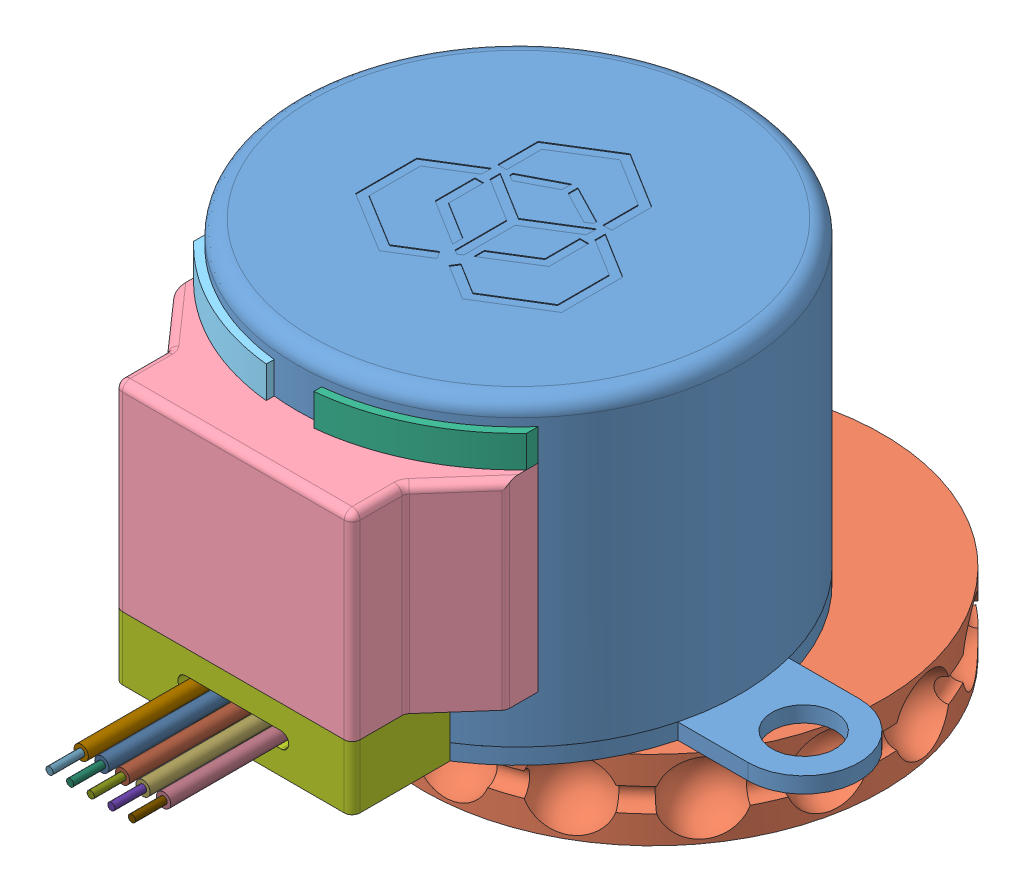
SolidWorks assembly MotorAndGearV2, configuration Default. Lengths in mm.
Overall size (43 33.3 55.34).
21 component instances, 20 part files, 3 mates.
Components (placement in the parent):
- StepMotor28BYJ-48-1: StepMotor28BYJ-48 [Default] at (-1.1449 -8.3691 -3.845) size (43 29.3 41)
  - Øàãîâûé äâèãàòåëü ñ ïëàòîé óïðàâëåíèÿ (äâèãàòåëü)_8-1: Øàãîâûé äâèãàòåëü ñ ïëàòîé óïðàâëåíèÿ (äâèãàòåëü)_8 [Default] at origin size (43 2.5 30)
  - Øàãîâûé äâèãàòåëü ñ ïëàòîé óïðàâëåíèÿ (äâèãàòåëü)_15-1: Øàãîâûé äâèãàòåëü ñ ïëàòîé óïðàâëåíèÿ (äâèãàòåëü)_15 [Default] at origin size (7 1.3 7)
  - Øàãîâûé äâèãàòåëü ñ ïëàòîé óïðàâëåíèÿ (äâèãàòåëü)_4-1: Øàãîâûé äâèãàòåëü ñ ïëàòîé óïðàâëåíèÿ (äâèãàòåëü)_4 [Default] at origin size (5 8 5)
  - Øàãîâûé äâèãàòåëü ñ ïëàòîé óïðàâëåíèÿ (äâèãàòåëü)-1: Øàãîâûé äâèãàòåëü ñ ïëàòîé óïðàâëåíèÿ (äâèãàòåëü) [Default] at origin size (21 12.5 8.74)
  - Øàãîâûé äâèãàòåëü ñ ïëàòîé óïðàâëåíèÿ (äâèãàòåëü)_17-1: Øàãîâûé äâèãàòåëü ñ ïëàòîé óïðàâëåíèÿ (äâèãàòåëü)_17 [Default] at origin size (9 2 5.16)
  - Øàãîâûé äâèãàòåëü ñ ïëàòîé óïðàâëåíèÿ (äâèãàòåëü)_14-1: Øàãîâûé äâèãàòåëü ñ ïëàòîé óïðàâëåíèÿ (äâèãàòåëü)_14 [Default] at origin size (9 2 5.16)
  - Øàãîâûé äâèãàòåëü ñ ïëàòîé óïðàâëåíèÿ (äâèãàòåëü)_5-1: Øàãîâûé äâèãàòåëü ñ ïëàòîé óïðàâëåíèÿ (äâèãàòåëü)_5 [Default] at origin size (15 4 6.18)
  - Øàãîâûé äâèãàòåëü ñ ïëàòîé óïðàâëåíèÿ (äâèãàòåëü)_7-1: Øàãîâûé äâèãàòåëü ñ ïëàòîé óïðàâëåíèÿ (äâèãàòåëü)_7 [Default] at origin size (13 3 3.6)
  - Øàãîâûé äâèãàòåëü ñ ïëàòîé óïðàâëåíèÿ (äâèãàòåëü)_2-1: Øàãîâûé äâèãàòåëü ñ ïëàòîé óïðàâëåíèÿ (äâèãàòåëü)_2 [Default] at origin size (0.9 0.9 10)
  - Øàãîâûé äâèãàòåëü ñ ïëàòîé óïðàâëåíèÿ (äâèãàòåëü)_6-1: Øàãîâûé äâèãàòåëü ñ ïëàòîé óïðàâëåíèÿ (äâèãàòåëü)_6 [Default] at origin size (0.9 0.9 10)
  - Øàãîâûé äâèãàòåëü ñ ïëàòîé óïðàâëåíèÿ (äâèãàòåëü)_16-1: Øàãîâûé äâèãàòåëü ñ ïëàòîé óïðàâëåíèÿ (äâèãàòåëü)_16 [Default] at origin size (0.9 0.9 10)
  - Øàãîâûé äâèãàòåëü ñ ïëàòîé óïðàâëåíèÿ (äâèãàòåëü)_12-1: Øàãîâûé äâèãàòåëü ñ ïëàòîé óïðàâëåíèÿ (äâèãàòåëü)_12 [Default] at origin size (0.9 0.9 10)
  - Øàãîâûé äâèãàòåëü ñ ïëàòîé óïðàâëåíèÿ (äâèãàòåëü)_18-1: Øàãîâûé äâèãàòåëü ñ ïëàòîé óïðàâëåíèÿ (äâèãàòåëü)_18 [Default] at origin size (0.9 0.9 10)
  - Øàãîâûé äâèãàòåëü ñ ïëàòîé óïðàâëåíèÿ (äâèãàòåëü)_9-1: Øàãîâûé äâèãàòåëü ñ ïëàòîé óïðàâëåíèÿ (äâèãàòåëü)_9 [Default] at origin size (0.45 0.45 2)
  - Øàãîâûé äâèãàòåëü ñ ïëàòîé óïðàâëåíèÿ (äâèãàòåëü)_11-1: Øàãîâûé äâèãàòåëü ñ ïëàòîé óïðàâëåíèÿ (äâèãàòåëü)_11 [Default] at origin size (0.45 0.45 2)
  - Øàãîâûé äâèãàòåëü ñ ïëàòîé óïðàâëåíèÿ (äâèãàòåëü)_13-1: Øàãîâûé äâèãàòåëü ñ ïëàòîé óïðàâëåíèÿ (äâèãàòåëü)_13 [Default] at origin size (0.45 0.45 2)
  - Øàãîâûé äâèãàòåëü ñ ïëàòîé óïðàâëåíèÿ (äâèãàòåëü)_19-1: Øàãîâûé äâèãàòåëü ñ ïëàòîé óïðàâëåíèÿ (äâèãàòåëü)_19 [Default] at origin size (0.45 0.45 2)
  - Øàãîâûé äâèãàòåëü ñ ïëàòîé óïðàâëåíèÿ (äâèãàòåëü)_3-1: Øàãîâûé äâèãàòåëü ñ ïëàòîé óïðàâëåíèÿ (äâèãàòåëü)_3 [Default] at origin size (0.45 0.45 2)
  - Øàãîâûé äâèãàòåëü ñ ïëàòîé óïðàâëåíèÿ (äâèãàòåëü)_10-1: Øàãîâûé äâèãàòåëü ñ ïëàòîé óïðàâëåíèÿ (äâèãàòåëü)_10 [Default] at origin size (28 19 28)
- Gear1-1: Gear1 [Default] at (-1.1449 -16.6691 -12.345) x (-0.866025 0 0.5) z (0 1 0) size (29.06 29.01 10)
Mates (geometry in assembly coordinates):
- Concentric1: concentric aligned: cylinder of StepMotor28BYJ-48-1/Øàãîâûé äâèãàòåëü ñ ïëàòîé óïðàâëåíèÿ (äâèãàòåëü)_4-1 through (-1.1449 -17.6691 -12.345) axis (0 1 0) radius 2.5; cylinder of Gear1-1 through (-1.1449 -18.6691 -12.345) axis (0 1 0) radius 2.5
- Coincident1: coincident anti-aligned: plane of StepMotor28BYJ-48-1/Øàãîâûé äâèãàòåëü ñ ïëàòîé óïðàâëåíèÿ (äâèãàòåëü)_4-1 through (0.0561 -11.6691 -7.2649) normal (-0.866025 0 0.5); plane of Gear1-1 through (-2.4439 -18.6691 -11.595) normal (0.866025 0 -0.5)
- Coincident2: coincident anti-aligned: plane of StepMotor28BYJ-48-1/Øàãîâûé äâèãàòåëü ñ ïëàòîé óïðàâëåíèÿ (äâèãàòåëü)_4-1 through (-1.1449 -11.6691 -3.845) normal (0 -1 0); plane of Gear1-1 through (-1.1449 -11.6691 -12.345) normal (0 1 0)
